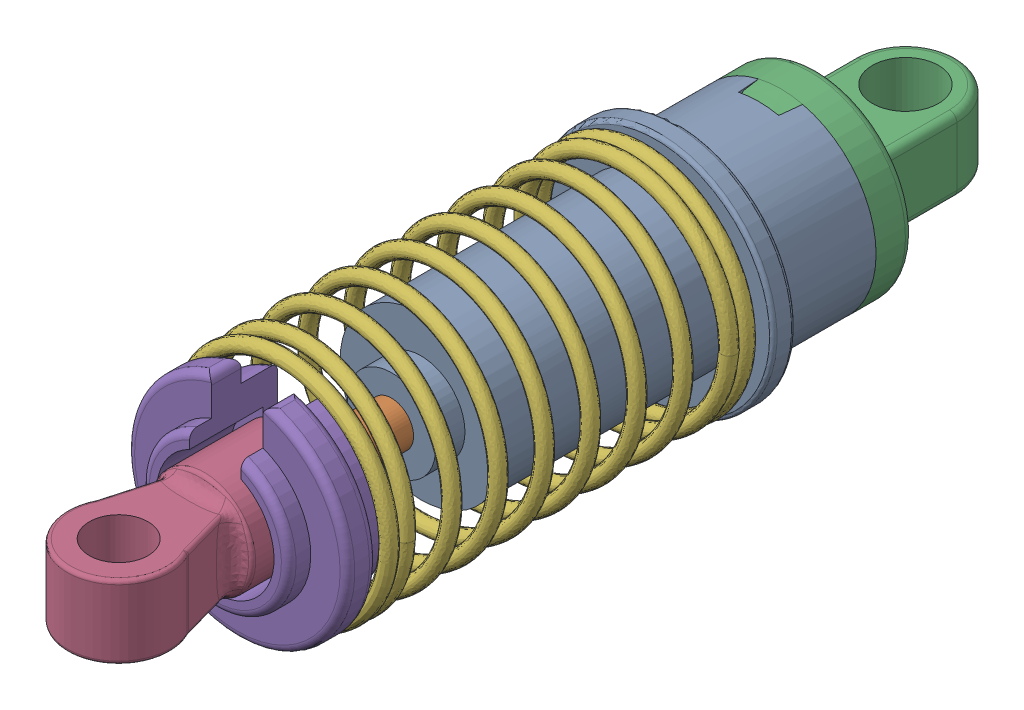
SolidWorks assembly Amortisseur, configuration Défaut. Lengths in mm.
Overall size (16 16.54 60.58).
7 component instances, 7 part files, 13 mates.
Components (placement in the parent):
- Corps d'amortisseur-C2-1: Corps d'amortisseur-C2 [Défaut] at origin size (16 16 26.5)
- Amortisseur-MB2-1: Amortisseur-MB2 [Défaut] at (0 0 8.5) x (0.96395 0.266083 0) z (0 0 1) size (5 5 24.53)
- Corps d'amortisseur-C1-1: Corps d'amortisseur-C1 [Défaut] at (0 0 -1.5) x (-1 0 0) z (0 0 -1) size (13 13 19)
- Amortisseur-C12-1: Amortisseur-C12 [Défaut] at (0 0 31) x (-1 0 0) z (0 0 -1) size (7 7.08 15.08)
- Amortisseur-C9-1: Amortisseur-C9 [Défaut] at (0 0 28.5) x (0 1 0) z (0 0 -1) size (14.63 15 6.07)
- Ressort d'amortisseur-MB14-1: Ressort d'amortisseur-MB14 [Défaut] at (-0.0633 0.0221 2.2043) size (15.51 15.5 26.35)
- Vis-M3-10-1: Vis-M3-10 [Défaut] at (0 -7 -5) x (1 0 0) z (0 -1 0) size (4.92 4.92 11.54)
Mates (geometry in assembly coordinates):
- Coïncidente1: coincident aligned: axis of Corps d'amortisseur-C2-1 through (0 0 16) axis (0 0 -1); axis of Amortisseur-MB2-1 through (0 0 32.75) axis (0 0 -1)
- Coïncidente2: coincident anti-aligned: axis of Corps d'amortisseur-C2-1 through (0 0 16) axis (0 0 -1); axis of Corps d'amortisseur-C1-1 through (0 0 -10.5) axis (0 0 1)
- Coïncidente3: coincident anti-aligned: plane of Corps d'amortisseur-C2-1 through (1.5 7 -8.5) normal (-0.996195 0 -0.087156); plane of Corps d'amortisseur-C1-1 through (1.5 6.3246 -8.5) normal (0.996195 0 0.087156)
- Coïncidente4: coincident anti-aligned: axis of Amortisseur-MB2-1 through (0 0 32.75) axis (0 0 -1); axis of Amortisseur-C12-1 through (0 0 25) axis (0 0 1)
- A distance1: distance = 8 mm anti-aligned: plane of Amortisseur-MB2-1 through (0 0 33) normal (0 0 1); plane of Amortisseur-C12-1 through (0 0 25) normal (0 0 -1)
- Parallèle1: parallel aligned: plane of Corps d'amortisseur-C1-1; plane of Amortisseur-C12-1 through (0 -2.5 36.5808) normal (0 -1 0)
- Coïncidente5: coincident anti-aligned: axis of Corps d'amortisseur-C2-1 through (0 0 16) axis (0 0 -1); axis of Amortisseur-C9-1 through (0 0 24.5) axis (0 0 1)
- Coïncidente6: coincident anti-aligned: plane of Amortisseur-C12-1 through (0 0 25) normal (0 0 -1); plane of Amortisseur-C9-1 through (0 0 25) normal (0 0 1)
- Perpendiculaire1: perpendicular: plane of Amortisseur-C12-1 through (0 2.5 36.5808) normal (0 1 0); plane of Amortisseur-C9-1 through (1.75 0 30) normal (-1 0 0)
- A distance2: distance = 0.5 mm anti-aligned: plane of Corps d'amortisseur-C2-1 through (0 0 10.5) normal (0 0 -1); plane of Amortisseur-MB2-1 through (0 0 10) normal (0 0 1)
- Coïncidente7: coincident anti-aligned: axis of Corps d'amortisseur-C2-1 through (0 -8.3896 -5) axis (0 1 0); axis of Vis-M3-10-1 through (0 2.5 -5) axis (0 -1 0)
- Coïncidente8: coincident anti-aligned: plane of Corps d'amortisseur-C2-1 through (0 -7 -5) normal (0 -1 0); plane of Vis-M3-10-1
- Parallèle2: parallel aligned: plane of Corps d'amortisseur-C1-1 through (-3.5 2.5 -11) normal (-1 0 0); plane of Vis-M3-10-1 through (0.25 -7.5 -3.25) normal (-1 0 0)
